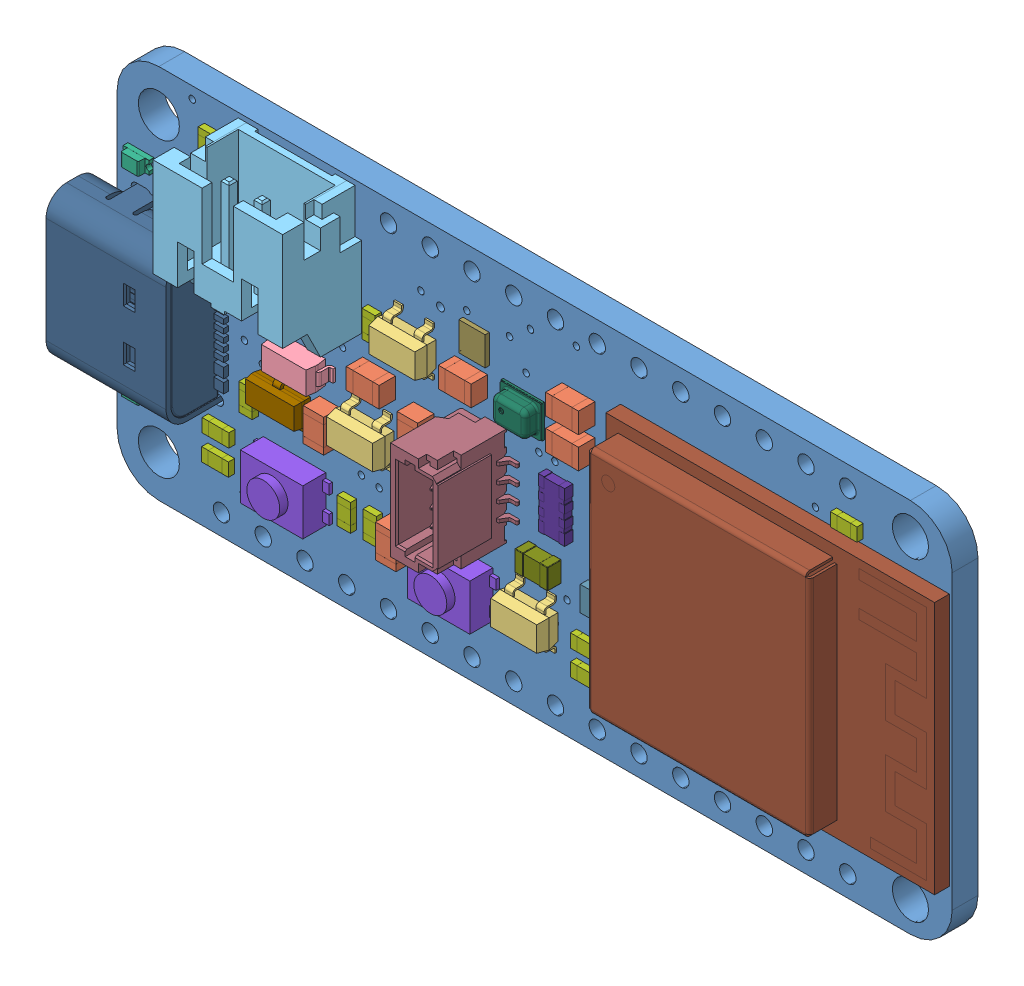
SolidWorks assembly 5303 Feather ESP32-S3, configuration Default. Lengths in mm.
Overall size (51.92 22.86 6.37).
38 component instances, 17 part files, 0 mates.
Components (placement in the parent):
- Board-1: Board [Default] at origin size (50.8 22.86 1.57)
- 10uF-1: 10uF [Default] at (12.943 9.393 1.57) x (0 -1 0) z (0 0 1) size (2 1.25 1)
- 10uF-2: 10uF [Default] at (17.338 5.452 1.57) x (0 -1 0) z (0 0 1) size (2 1.25 1)
- 10uF-3: 10uF [Default] at (21.539 16.002 1.57) size (2 1.25 1)
- 10uF-4: 10uF [Default] at (18.656 11.938 1.57) x (0 1 0) z (0 0 1) size (2 1.25 1)
- 10uF-5: 10uF [Default] at (15.938 13.132 1.57) size (2 1.25 1)
- 10uF-6: 10uF [Default] at (28.067 17.844 1.57) size (2 1.25 1)
- 10uF-7: 10uF [Default] at (28.067 15.938 1.57) size (2 1.25 1)
- AP2112_RT9080-3.3-1: AP2112_RT9080-3.3 [Default] at (15.545 10.16 1.57) size (3 3 1.4)
- AP2112_RT9080-3.3-2: AP2112_RT9080-3.3 [Default] at (18.11 16.256 1.57) size (3 3 1.4)
- AP2112_RT9080-3.3-3: AP2112_RT9080-3.3 [Default] at (25.527 5.588 1.57) size (3 3 1.4)
- MBR540-1: MBR540 [Default] at (11.481 11.989 1.57) x (-1 0 0) z (0 0 1) size (3.6 1.4 1.35)
- JSTPH-1: JSTPH [Default] at (10.922 19.368 1.57) size (7.9 8.6 4.8)
- RED-1: RED [Default] at (1.46 5.461 1.57) x (0 -1 0) z (0 0 1) size (0.79 1.61 0.71)
- RED-2: RED [Default] at (1.46 17.526 1.57) x (0 1 0) z (0 0 1) size (0.79 1.61 0.71)
- 1uF-1: 1uF [Default] at (6.337 4.115 1.57) size (1.63 0.81 0.38)
- 1uF-2: 1uF [Default] at (5.715 20.447 1.57) x (0 -1 0) z (0 0 1) size (1.63 0.81 0.38)
- 1uF-3: 1uF [Default] at (18.669 8.877 1.57) size (1.63 0.81 0.38)
- 1uF-4: 1uF [Default] at (6.363 5.664 1.57) x (-1 0 0) z (0 0 1) size (1.63 0.81 0.38)
- 1uF-5: 1uF [Default] at (14.173 5.283 1.57) x (0 1 0) z (0 0 1) size (1.63 0.81 0.38)
- 1uF-6: 1uF [Default] at (15.672 15.875 1.57) x (0 1 0) z (0 0 1) size (1.63 0.81 0.38)
- 1uF-7: 1uF [Default] at (8.192 8.28 1.57) x (0 1 0) z (0 0 1) size (1.63 0.81 0.38)
- 1uF-8: 1uF [Default] at (5.08 17.272 1.57) size (1.63 0.81 0.38)
- 1uF-9: 1uF [Default] at (15.748 5.334 1.57) x (0 1 0) z (0 0 1) size (1.63 0.81 0.38)
- 1uF-10: 1uF [Default] at (28.766 5.524 1.57) size (1.63 0.81 0.38)
- 1uF-11: 1uF [Default] at (28.766 4 1.57) x (-1 0 0) z (0 0 1) size (1.63 0.81 0.38)
- 1uF-12: 1uF [Default] at (44.577 19.812 1.57) size (1.63 0.81 0.38)
- KMR2-1: KMR2 [Default] at (10.795 5.144 1.57) size (4.6 2.8 1.9)
- KMR2-2: KMR2 [Default] at (20.955 5.207 1.57) size (4.6 2.8 1.9)
- DMG3415U-1: DMG3415U [Default] at (10.401 9.512 1.57) size (3.04 2.64 1.12)
- USB C-1: USB C [Default] at (2.667 11.43 1.57) x (0 -1 0) z (0 0 1) size (8.94 7.9 4.2)
- ESP32-S2-MODULE_MINI-1: ESP32-S2-MODULE_MINI [Default] at (40.64 11.43 1.57) x (0 -1 0) z (0 0 1) size (15.4 20 2.55)
- LC709203F_MH-1: LC709203F_MH [Default] at (21.844 18.034 1.57) x (0 1 0) z (0 0 1) size (1.75 1.6 0.51)
- JST SH-1: JST SH [Default] at (22.352 11.43 1.57) x (0 -1 0) z (0 0 1) size (6 3.6 4.3)
- WS2812B_SK6805_1515-1: WS2812B_SK6805_1515 [Default] at (29.4 8.128 1.57) size (1.5 1.5 0.48)
- BME280-1: BME280 [Default] at (24.765 16.002 1.57) x (0 1 0) z (0 0 1) size (2 2.5 0.97)
- 10uF_1-1: 10uF_1 [Default] at (26.035 8.509 1.57) size (2 1.25 0.85)
- 10K-1: 10K [Default] at (26.924 11.938 1.57) x (0 -1 0) z (0 0 1) size (3.05 1.6 0.5)
